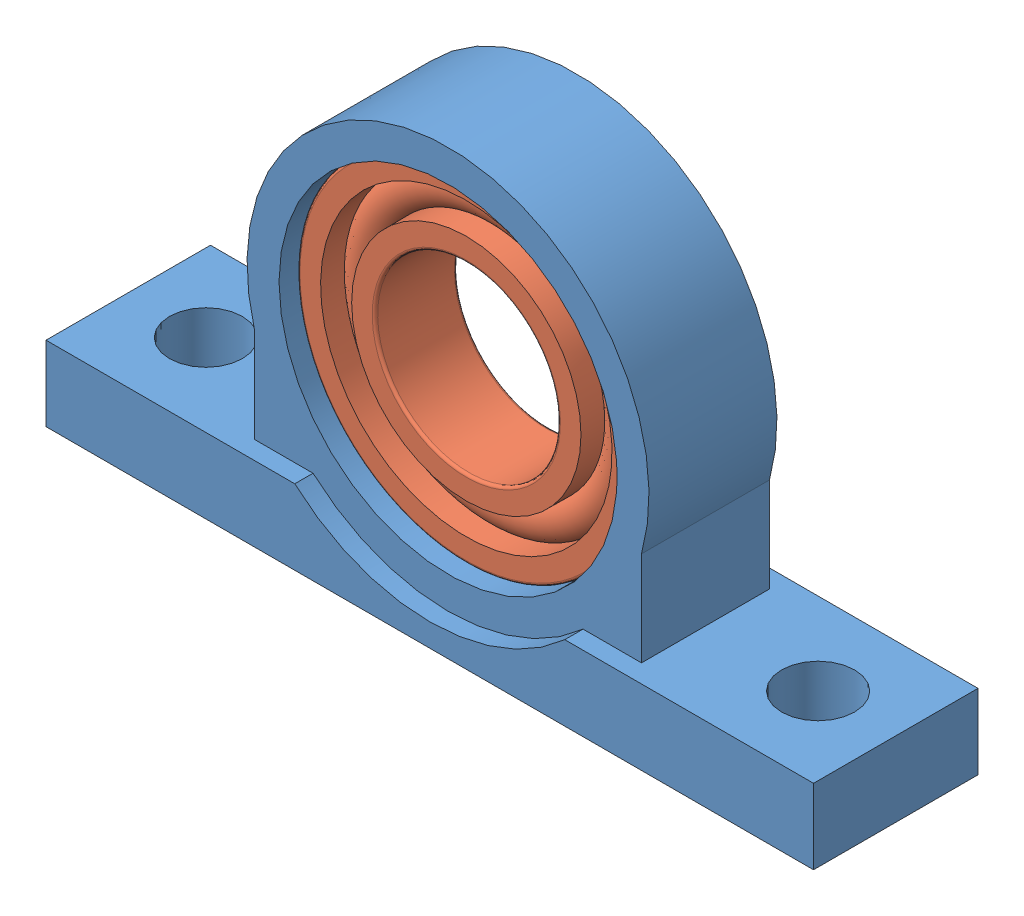
SolidWorks assembly Ensamblaje 8M drive assy, configuration Predeterminado. Lengths in mm.
Overall size (84 46.5 18).
2 component instances, 2 part files, 2 mates.
Components (placement in the parent):
- fijadores del eje-1: fijadores del eje [Predeterminado] at (36.2208 -24.0928 75) size (84 46.5 18)
- radial ball bearing_68_skf-3: radial ball bearing_68_skf [SKF - 61904 - 14,SI,NC,14_68] at (-5.7792 0.4072 84.5) x (0 0 1) z (0.143935 -0.989587 0) size (9 37 37)
Mates (geometry in assembly coordinates):
- Concéntrica2: concentric: cylinder of fijadores del eje-1 through (-5.7792 0.4072 93) axis (0 0 -1) radius 18.5; cylinder of radial ball bearing_68_skf-3 through (-5.7792 0.4072 63.8625) axis (0 0 1) radius 18.5
- Distancia3: distance = 2 mm: plane of radial ball bearing_68_skf-3 through (-23.7897 -2.2124 89) normal (0 0 1); plane of fijadores del eje-1 through (-5.7792 0.4072 91) normal (0 0 1)
